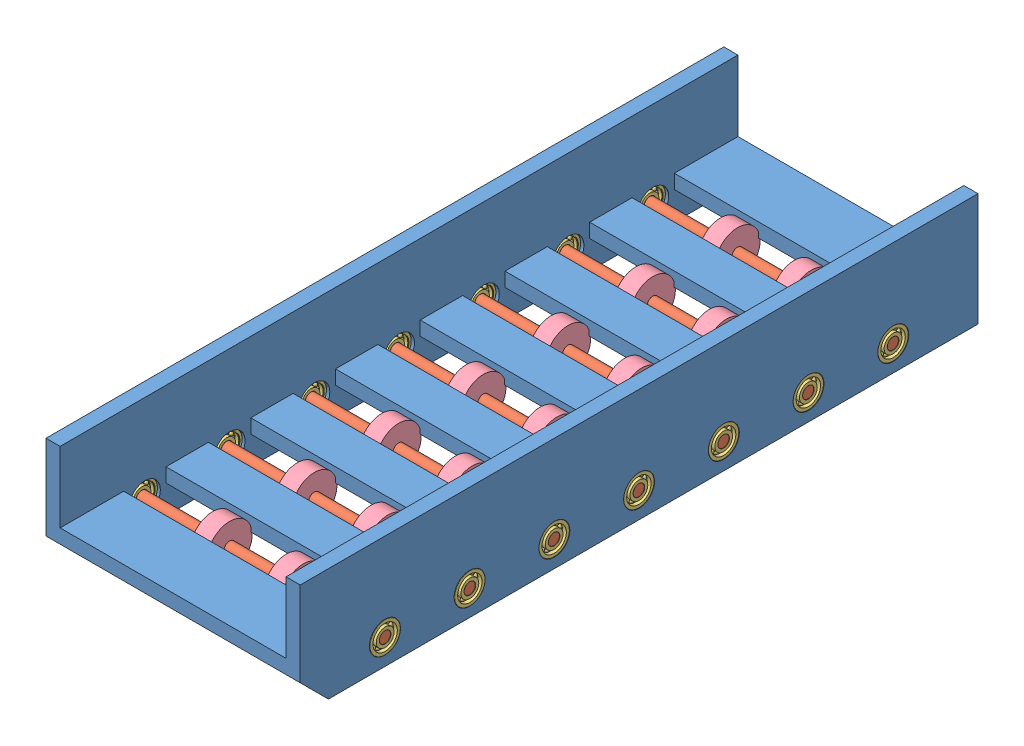
SolidWorks assembly chute_assemble_20241127, configuration 默认. Lengths in mm.
Overall size (90.23 42.03 240).
36 component instances, 4 part files, 59 mates.
Components (placement in the parent):
- chute_metal_20241127-1: chute_metal_20241127 [默认] at (2.4605 -4.6428 75) size (90 40 240)
- chute_stick_metal_20241127-1: chute_stick_metal_20241127 [默认] at (47.3105 -10.6428 135) x (0 0 1) z (-1 0 0) size (4 4 90)
- Rolling bearings S719-4 GB 292-94-1: Rolling bearings S719-4 GB 292-94 [Rolling bearings S719-4 GB 292-94] at (-40.6895 -10.6428 135) x (1 0 0) z (0 0.999705 0.024301) size (4 11 11)
- Rolling bearings S719-4 GB 292-94-2: Rolling bearings S719-4 GB 292-94 [Rolling bearings S719-4 GB 292-94] at (45.3905 -10.6428 135) x (-1 0 0) z (0 0.977196 -0.212337) size (4 11 11)
- chute_stickball_metal_20241127-1: chute_stickball_metal_20241127 [默认] at (18.3905 -10.6428 135) x (0 0.978422 0.206615) z (-1 0 0) size (16 16 6)
- chute_stickball_metal_20241127-2: chute_stickball_metal_20241127 [默认] at (-7.6895 -10.6428 135) x (0 -0.199483 0.979901) z (-1 0 0) size (16 16 6)
- Rolling bearings S719-4 GB 292-94-3: Rolling bearings S719-4 GB 292-94 [Rolling bearings S719-4 GB 292-94] at (45.3905 -10.6428 165) x (-1 0 0) z (0 0.977196 -0.212337) size (4 11 11)
- chute_stickball_metal_20241127-3: chute_stickball_metal_20241127 [默认] at (-7.6895 -10.6428 165) x (0 -0.199483 0.979901) z (-1 0 0) size (16 16 6)
- chute_stickball_metal_20241127-4: chute_stickball_metal_20241127 [默认] at (18.3905 -10.6428 165) x (0 0 1) z (-1 0 0) size (16 16 6)
- Rolling bearings S719-4 GB 292-94-4: Rolling bearings S719-4 GB 292-94 [Rolling bearings S719-4 GB 292-94] at (-40.6895 -10.6428 165) x (1 0 0) z (0 0.999705 0.024301) size (4 11 11)
- chute_stick_metal_20241127-2: chute_stick_metal_20241127 [默认] at (47.3105 -10.6428 165) x (0 0 1) z (-1 0 0) size (4 4 90)
- Rolling bearings S719-4 GB 292-94-5: Rolling bearings S719-4 GB 292-94 [Rolling bearings S719-4 GB 292-94] at (45.3905 -10.6428 105) x (-1 0 0) z (0 0.977196 -0.212337) size (4 11 11)
- chute_stickball_metal_20241127-5: chute_stickball_metal_20241127 [默认] at (-7.6895 -10.6428 105) x (0 -0.199483 0.979901) z (-1 0 0) size (16 16 6)
- chute_stickball_metal_20241127-6: chute_stickball_metal_20241127 [默认] at (18.3905 -10.6428 105) x (0 0 1) z (-1 0 0) size (16 16 6)
- Rolling bearings S719-4 GB 292-94-6: Rolling bearings S719-4 GB 292-94 [Rolling bearings S719-4 GB 292-94] at (-40.6895 -10.6428 105) x (1 0 0) z (0 0.999705 0.024301) size (4 11 11)
- chute_stick_metal_20241127-3: chute_stick_metal_20241127 [默认] at (47.3105 -10.6428 105) x (0 0 1) z (-1 0 0) size (4 4 90)
- Rolling bearings S719-4 GB 292-94-7: Rolling bearings S719-4 GB 292-94 [Rolling bearings S719-4 GB 292-94] at (45.3905 -10.6428 195) x (-1 0 0) z (0 0.977196 -0.212337) size (4 11 11)
- chute_stickball_metal_20241127-7: chute_stickball_metal_20241127 [默认] at (-7.6895 -10.6428 195) x (0 -0.199483 0.979901) z (-1 0 0) size (16 16 6)
- chute_stickball_metal_20241127-8: chute_stickball_metal_20241127 [默认] at (18.3905 -10.6428 195) x (0 0.504953 0.863147) z (-1 0 0) size (16 16 6)
- Rolling bearings S719-4 GB 292-94-8: Rolling bearings S719-4 GB 292-94 [Rolling bearings S719-4 GB 292-94] at (-40.6895 -10.6428 195) x (1 0 0) z (0 0.999705 0.024301) size (4 11 11)
- chute_stick_metal_20241127-4: chute_stick_metal_20241127 [默认] at (47.3105 -10.6428 195) x (0 0 1) z (-1 0 0) size (4 4 90)
- chute_stickball_metal_20241127-9: chute_stickball_metal_20241127 [默认] at (-7.6895 -10.6428 225) x (0 -0.092424 0.99572) z (-1 0 0) size (16 16 6)
- chute_stickball_metal_20241127-10: chute_stickball_metal_20241127 [默认] at (18.3905 -10.6428 225) x (0 -0.53296 -0.84614) z (-1 0 0) size (16 16 6)
- Rolling bearings S719-4 GB 292-94-9: Rolling bearings S719-4 GB 292-94 [Rolling bearings S719-4 GB 292-94] at (45.3905 -10.6428 225) x (-1 0 0) z (0 0.977196 -0.212337) size (4 11 11)
- Rolling bearings S719-4 GB 292-94-10: Rolling bearings S719-4 GB 292-94 [Rolling bearings S719-4 GB 292-94] at (-40.6895 -10.6428 225) x (1 0 0) z (0 0.999705 0.024301) size (4 11 11)
- chute_stick_metal_20241127-5: chute_stick_metal_20241127 [默认] at (47.3105 -10.6428 225) x (0 0 1) z (-1 0 0) size (4 4 90)
- Rolling bearings S719-4 GB 292-94-11: Rolling bearings S719-4 GB 292-94 [Rolling bearings S719-4 GB 292-94] at (45.5405 -10.6428 285) x (-1 0 0) z (0 0.977196 -0.212337) size (4 11 11)
- chute_stickball_metal_20241127-11: chute_stickball_metal_20241127 [默认] at (-7.5395 -10.6428 285) x (0 -0.199483 0.979901) z (-1 0 0) size (16 16 6)
- chute_stick_metal_20241127-6: chute_stick_metal_20241127 [默认] at (47.4605 -10.6428 285) x (0 0 1) z (-1 0 0) size (4 4 90)
- Rolling bearings S719-4 GB 292-94-12: Rolling bearings S719-4 GB 292-94 [Rolling bearings S719-4 GB 292-94] at (-40.5395 -10.6428 285) x (1 0 0) z (0 0.999705 0.024301) size (4 11 11)
- chute_stickball_metal_20241127-12: chute_stickball_metal_20241127 [默认] at (18.5405 -10.6428 285) x (0 -0.53296 -0.84614) z (-1 0 0) size (16 16 6)
- Rolling bearings S719-4 GB 292-94-13: Rolling bearings S719-4 GB 292-94 [Rolling bearings S719-4 GB 292-94] at (45.5405 -10.6428 255) x (-1 0 0) z (0 0.977196 -0.212337) size (4 11 11)
- chute_stickball_metal_20241127-13: chute_stickball_metal_20241127 [默认] at (-7.5395 -10.6428 255) x (0 -0.199483 0.979901) z (-1 0 0) size (16 16 6)
- chute_stick_metal_20241127-7: chute_stick_metal_20241127 [默认] at (47.4605 -10.6428 255) x (0 0 1) z (-1 0 0) size (4 4 90)
- Rolling bearings S719-4 GB 292-94-14: Rolling bearings S719-4 GB 292-94 [Rolling bearings S719-4 GB 292-94] at (-40.5395 -10.6428 255) x (1 0 0) z (0 0.999705 0.024301) size (4 11 11)
- chute_stickball_metal_20241127-14: chute_stickball_metal_20241127 [默认] at (18.5405 -10.6428 255) x (0 -0.53296 -0.84614) z (-1 0 0) size (16 16 6)
Mates (geometry in assembly coordinates):
- 重合1: coincident anti-aligned: circle of chute_stick_metal_20241127-1; circle of Rolling bearings S719-4 GB 292-94-2
- 同心1: concentric anti-aligned: cylinder of chute_stick_metal_20241127-1 through (-42.6895 -10.6428 135) axis (1 0 0) radius 2; cylinder of Rolling bearings S719-4 GB 292-94-1 through (-43.6818 -10.6428 135) axis (-1 0 0) radius 2
- 重合2: coincident aligned: plane of chute_stick_metal_20241127-1 through (-42.6895 -10.6428 135) normal (-1 0 0); plane of Rolling bearings S719-4 GB 292-94-1 through (-42.6895 -10.5942 133.0006) normal (-1 0 0)
- 同心2: concentric aligned: cylinder of chute_stick_metal_20241127-1 through (-42.6895 -10.6428 135) axis (1 0 0) radius 2; cylinder of chute_stickball_metal_20241127-1 through (12.3905 -10.6428 135) axis (1 0 0) radius 2
- 同心3: concentric aligned: cylinder of chute_stick_metal_20241127-1 through (-42.6895 -10.6428 135) axis (1 0 0) radius 2; cylinder of chute_stickball_metal_20241127-2 through (-13.6895 -10.6428 135) axis (1 0 0) radius 2
- 距离1: distance = 25 mm anti-aligned: plane of Rolling bearings S719-4 GB 292-94-2 through (43.3905 -9.9704 138.0945) normal (-1 0 0); plane of chute_stickball_metal_20241127-1 through (18.3905 -10.6428 135) normal (1 0 0)
- 距离2: distance = 25 mm anti-aligned: plane of Rolling bearings S719-4 GB 292-94-1 through (-38.6895 -10.5659 131.8343) normal (1 0 0); plane of chute_stickball_metal_20241127-2 through (-13.6895 -10.6428 135) normal (-1 0 0)
- 距离3: distance = 25 mm anti-aligned: plane of Rolling bearings S719-4 GB 292-94-4 through (-38.6895 -10.5659 161.8343) normal (1 0 0); plane of chute_stickball_metal_20241127-3 through (-13.6895 -10.6428 165) normal (-1 0 0)
- 同心4: concentric anti-aligned: cylinder of Rolling bearings S719-4 GB 292-94-4 through (-43.6818 -10.6428 165) axis (-1 0 0) radius 2; cylinder of chute_stick_metal_20241127-2 through (-42.6895 -10.6428 165) axis (1 0 0) radius 2
- 同心5: concentric aligned: cylinder of chute_stickball_metal_20241127-4 through (12.3905 -10.6428 165) axis (1 0 0) radius 2; cylinder of chute_stick_metal_20241127-2 through (-42.6895 -10.6428 165) axis (1 0 0) radius 2
- 同心6: concentric aligned: cylinder of chute_stickball_metal_20241127-3 through (-13.6895 -10.6428 165) axis (1 0 0) radius 2; cylinder of chute_stick_metal_20241127-2 through (-42.6895 -10.6428 165) axis (1 0 0) radius 2
- 距离4: distance = 25 mm anti-aligned: plane of Rolling bearings S719-4 GB 292-94-3 through (43.3905 -9.9704 168.0945) normal (-1 0 0); plane of chute_stickball_metal_20241127-4 through (18.3905 -10.6428 165) normal (1 0 0)
- 重合5: coincident anti-aligned: circle of Rolling bearings S719-4 GB 292-94-3; circle of chute_stick_metal_20241127-2
- 重合6: coincident aligned: plane of Rolling bearings S719-4 GB 292-94-4 through (-42.6895 -10.5942 163.0006) normal (-1 0 0); plane of chute_stick_metal_20241127-2 through (-42.6895 -10.6428 165) normal (-1 0 0)
- 距离5: distance = 25 mm anti-aligned: plane of Rolling bearings S719-4 GB 292-94-6 through (-38.6895 -10.5659 101.8343) normal (1 0 0); plane of chute_stickball_metal_20241127-5 through (-13.6895 -10.6428 105) normal (-1 0 0)
- 同心7: concentric anti-aligned: cylinder of Rolling bearings S719-4 GB 292-94-6 through (-43.6818 -10.6428 105) axis (-1 0 0) radius 2; cylinder of chute_stick_metal_20241127-3 through (-42.6895 -10.6428 105) axis (1 0 0) radius 2
- 同心8: concentric aligned: cylinder of chute_stickball_metal_20241127-6 through (12.3905 -10.6428 105) axis (1 0 0) radius 2; cylinder of chute_stick_metal_20241127-3 through (-42.6895 -10.6428 105) axis (1 0 0) radius 2
- 同心9: concentric aligned: cylinder of chute_stickball_metal_20241127-5 through (-13.6895 -10.6428 105) axis (1 0 0) radius 2; cylinder of chute_stick_metal_20241127-3 through (-42.6895 -10.6428 105) axis (1 0 0) radius 2
- 距离6: distance = 25 mm anti-aligned: plane of Rolling bearings S719-4 GB 292-94-5 through (43.3905 -9.9704 108.0945) normal (-1 0 0); plane of chute_stickball_metal_20241127-6 through (18.3905 -10.6428 105) normal (1 0 0)
- 重合7: coincident anti-aligned: circle of Rolling bearings S719-4 GB 292-94-5; circle of chute_stick_metal_20241127-3
- 重合8: coincident aligned: plane of Rolling bearings S719-4 GB 292-94-6 through (-42.6895 -10.5942 103.0006) normal (-1 0 0); plane of chute_stick_metal_20241127-3 through (-42.6895 -10.6428 105) normal (-1 0 0)
- 距离7: distance = 25 mm anti-aligned: plane of Rolling bearings S719-4 GB 292-94-8 through (-38.6895 -10.5659 191.8343) normal (1 0 0); plane of chute_stickball_metal_20241127-7 through (-13.6895 -10.6428 195) normal (-1 0 0)
- 同心10: concentric anti-aligned: cylinder of Rolling bearings S719-4 GB 292-94-8 through (-43.6818 -10.6428 195) axis (-1 0 0) radius 2; cylinder of chute_stick_metal_20241127-4 through (-42.6895 -10.6428 195) axis (1 0 0) radius 2
- 同心11: concentric aligned: cylinder of chute_stickball_metal_20241127-8 through (12.3905 -10.6428 195) axis (1 0 0) radius 2; cylinder of chute_stick_metal_20241127-4 through (-42.6895 -10.6428 195) axis (1 0 0) radius 2
- 同心12: concentric aligned: cylinder of chute_stickball_metal_20241127-7 through (-13.6895 -10.6428 195) axis (1 0 0) radius 2; cylinder of chute_stick_metal_20241127-4 through (-42.6895 -10.6428 195) axis (1 0 0) radius 2
- 距离8: distance = 25 mm anti-aligned: plane of Rolling bearings S719-4 GB 292-94-7 through (43.3905 -9.9704 198.0945) normal (-1 0 0); plane of chute_stickball_metal_20241127-8 through (18.3905 -10.6428 195) normal (1 0 0)
- 重合9: coincident anti-aligned: circle of Rolling bearings S719-4 GB 292-94-7; circle of chute_stick_metal_20241127-4
- 重合10: coincident aligned: plane of Rolling bearings S719-4 GB 292-94-8 through (-42.6895 -10.5942 193.0006) normal (-1 0 0); plane of chute_stick_metal_20241127-4 through (-42.6895 -10.6428 195) normal (-1 0 0)
- 重合20: coincident anti-aligned: circle of chute_metal_20241127-1; circle of Rolling bearings S719-4 GB 292-94-6
- 重合21: coincident anti-aligned: circle of chute_metal_20241127-1; circle of Rolling bearings S719-4 GB 292-94-1
- 重合22: coincident anti-aligned: circle of chute_metal_20241127-1; circle of Rolling bearings S719-4 GB 292-94-4
- 重合23: coincident anti-aligned: circle of chute_metal_20241127-1; circle of Rolling bearings S719-4 GB 292-94-8
- 距离9: distance = 25 mm anti-aligned: plane of Rolling bearings S719-4 GB 292-94-10 through (-38.6895 -10.5659 221.8343) normal (1 0 0); plane of chute_stickball_metal_20241127-9 through (-13.6895 -10.6428 225) normal (-1 0 0)
- 同心19: concentric anti-aligned: cylinder of Rolling bearings S719-4 GB 292-94-10 through (-43.6818 -10.6428 225) axis (-1 0 0) radius 2; cylinder of chute_stick_metal_20241127-5 through (-42.6895 -1.2796 214.5886) axis (1 0 0) radius 2
- 同心20: concentric aligned: cylinder of chute_stickball_metal_20241127-10 through (12.3905 -10.6428 225) axis (1 0 0) radius 2; cylinder of chute_stick_metal_20241127-5 through (-42.6895 -1.2796 214.5886) axis (1 0 0) radius 2
- 同心21: concentric aligned: cylinder of chute_stickball_metal_20241127-9 through (-13.6895 -10.6428 225) axis (1 0 0) radius 2; cylinder of chute_stick_metal_20241127-5 through (-42.6895 -1.2796 214.5886) axis (1 0 0) radius 2
- 距离10: distance = 25 mm anti-aligned: plane of Rolling bearings S719-4 GB 292-94-9 through (43.3905 -9.9704 228.0945) normal (-1 0 0); plane of chute_stickball_metal_20241127-10 through (18.3905 -10.6428 225) normal (1 0 0)
- 重合24: coincident anti-aligned: circle of Rolling bearings S719-4 GB 292-94-9; circle of chute_stick_metal_20241127-5
- 重合25: coincident aligned: plane of Rolling bearings S719-4 GB 292-94-10 through (-42.6895 -10.5942 223.0006) normal (-1 0 0); plane of chute_stick_metal_20241127-5 through (-42.6895 -1.2796 214.5886) normal (-1 0 0)
- 重合26: coincident anti-aligned: circle of Rolling bearings S719-4 GB 292-94-11; circle of chute_stick_metal_20241127-6
- 重合27: coincident aligned: plane of chute_stick_metal_20241127-6 through (-42.5395 4.9372 292.16) normal (-1 0 0); plane of Rolling bearings S719-4 GB 292-94-12 through (-288.5844 -10.5942 283.0006) normal (-1 0 0)
- 同心22: concentric anti-aligned: cylinder of chute_stick_metal_20241127-6 through (-42.5395 4.9372 292.16) axis (1 0 0) radius 2; cylinder of Rolling bearings S719-4 GB 292-94-12 through (-289.5767 -10.6428 285) axis (-1 0 0) radius 2
- 同心23: concentric aligned: cylinder of chute_stick_metal_20241127-6 through (-42.5395 4.9372 292.16) axis (1 0 0) radius 2; cylinder of chute_stickball_metal_20241127-12 through (-233.5044 -10.6428 285) axis (1 0 0) radius 2
- 距离11: distance = 25 mm anti-aligned: plane of Rolling bearings S719-4 GB 292-94-11 through (43.5405 -9.9704 288.0945) normal (-1 0 0); plane of chute_stickball_metal_20241127-12 through (18.5405 -10.6428 285) normal (1 0 0)
- 同心24: concentric aligned: cylinder of chute_stickball_metal_20241127-11 through (-259.5844 -10.6428 285) axis (1 0 0) radius 2; cylinder of chute_stick_metal_20241127-6 through (-42.5395 4.9372 292.16) axis (1 0 0) radius 2
- 距离12: distance = 25 mm anti-aligned: plane of Rolling bearings S719-4 GB 292-94-12 through (-38.5395 -10.5659 281.8343) normal (1 0 0); plane of chute_stickball_metal_20241127-11 through (-13.5395 -10.6428 285) normal (-1 0 0)
- 重合28: coincident anti-aligned: circle of Rolling bearings S719-4 GB 292-94-13; circle of chute_stick_metal_20241127-7
- 重合29: coincident aligned: plane of chute_stick_metal_20241127-7 through (-42.568 2.1733 245.0704) normal (-1 0 0); plane of Rolling bearings S719-4 GB 292-94-14 through (-42.7775 -10.5942 253.0006) normal (-1 0 0)
- 同心25: concentric anti-aligned: cylinder of chute_stick_metal_20241127-7 through (-42.568 2.1733 245.0704) axis (1 0 0) radius 2; cylinder of Rolling bearings S719-4 GB 292-94-14 through (-43.7698 -10.6428 255) axis (-1 0 0) radius 2
- 同心26: concentric aligned: cylinder of chute_stick_metal_20241127-7 through (-42.568 2.1733 245.0704) axis (1 0 0) radius 2; cylinder of chute_stickball_metal_20241127-14 through (12.3025 -10.6428 255) axis (1 0 0) radius 2
- 距离13: distance = 25 mm anti-aligned: plane of Rolling bearings S719-4 GB 292-94-13 through (43.5405 -9.9704 258.0945) normal (-1 0 0); plane of chute_stickball_metal_20241127-14 through (18.5405 -10.6428 255) normal (1 0 0)
- 同心27: concentric aligned: cylinder of chute_stickball_metal_20241127-13 through (-13.7775 -10.6428 255) axis (1 0 0) radius 2; cylinder of chute_stick_metal_20241127-7 through (-42.568 2.1733 245.0704) axis (1 0 0) radius 2
- 距离14: distance = 25 mm anti-aligned: plane of Rolling bearings S719-4 GB 292-94-14 through (-38.5395 -10.5659 251.8343) normal (1 0 0); plane of chute_stickball_metal_20241127-13 through (-13.5395 -10.6428 255) normal (-1 0 0)
- 重合30: coincident aligned: circle of chute_metal_20241127-1; circle of Rolling bearings S719-4 GB 292-94-10
- 平行2: parallel aligned: plane of chute_metal_20241127-1 through (-42.5395 -4.6428 315) normal (-1 0 0); plane of chute_stick_metal_20241127-5 through (-42.6895 -10.6428 225) normal (-1 0 0)
- 同心28: concentric anti-aligned: circle of chute_metal_20241127-1; circle of Rolling bearings S719-4 GB 292-94-14
- 重合32: coincident aligned: plane of chute_metal_20241127-1 through (-42.5395 -4.6428 315) normal (-1 0 0); plane of chute_stick_metal_20241127-7 through (-42.5395 -10.6428 255) normal (-1 0 0)
- 同心29: concentric anti-aligned: circle of chute_metal_20241127-1; circle of Rolling bearings S719-4 GB 292-94-12
- 重合33: coincident aligned: plane of chute_metal_20241127-1 through (-42.5395 -4.6428 315) normal (-1 0 0); circle of chute_stick_metal_20241127-6
